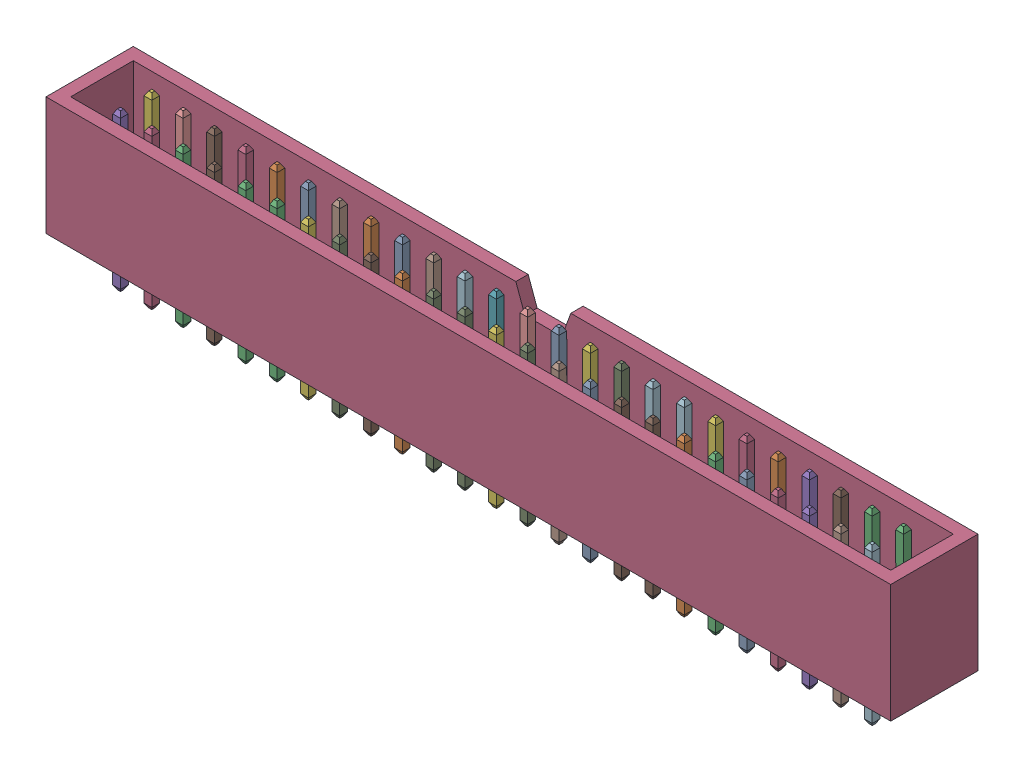
SolidWorks assembly 25 pin with case v2, configuration Predeterminado. Lengths in mm.
Overall size (68.5 12.8 7.08).
4 component instances, 3 part files, 0 mates.
Components (placement in the parent):
- Pin Header 2x15 TH Pitch 2.54mm v2-1: Pin Header 2x15 TH Pitch 2.54mm v2 [Predeterminado] at (0 0.0647 1.8778) x (1 0 0) z (0 1 0) size (38.1 5.08 12.7)
- Pin Header 2x10 TH Pitch 2.54mm v2-1: Pin Header 2x10 TH Pitch 2.54mm v2 [Predeterminado] at (38.1 0.0647 1.8778) x (1 0 0) z (0 1 0) size (25.4 5.08 12.7)
- 2X25Pin case v7-1: 2X25Pin case v7 [Predeterminado] x (1 0 0) z (0 1 0) size (68.5 7.08 9.6)
  - Component1_7-1: Component1_7 [Predeterminado] at (-1.5 -1.8778 0.0661) size (68.5 7.08 9.6)
